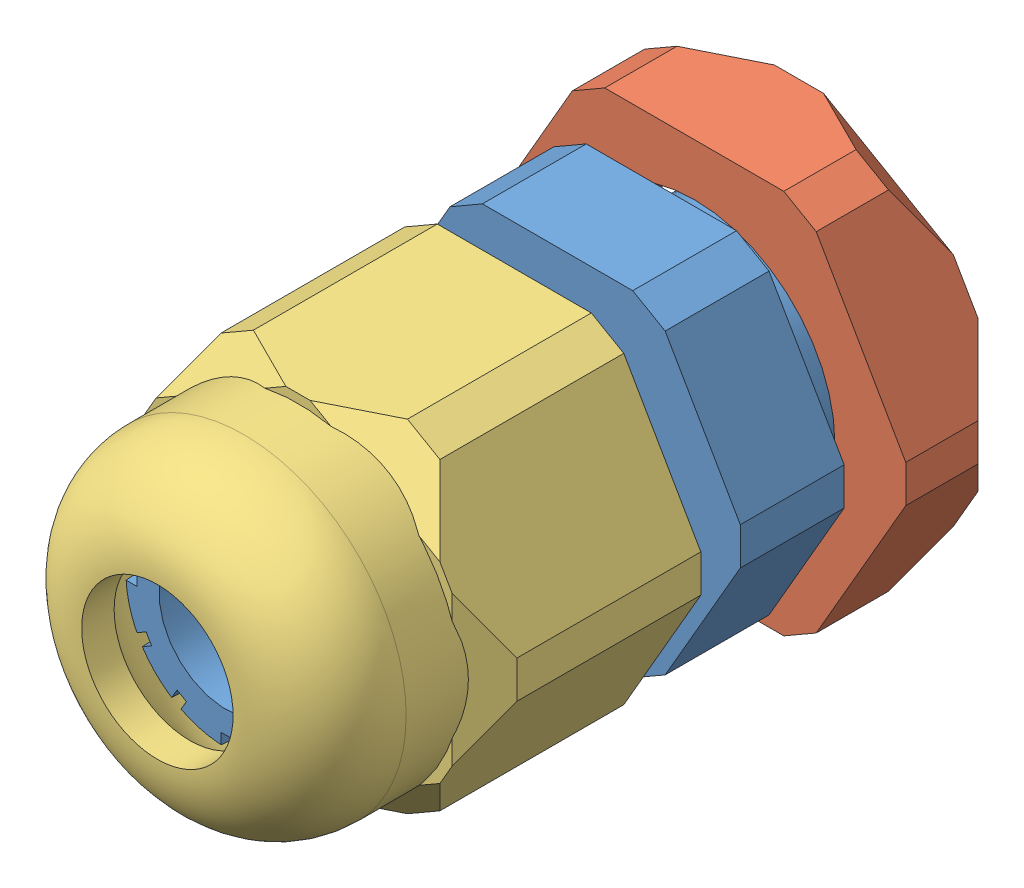
SolidWorks assembly PG7-CableGland, configuration Default. Lengths in mm.
Overall size (19.55 17.8 31.5).
3 component instances, 3 part files, 6 mates.
Components (placement in the parent):
- PG7-CableGland-Body-1: PG7-CableGland-Body [Default] at (0.0823 -0.2161 28.3183) size (16.9 15.5 28.32)
- PG7-CableGland-Back-1: PG7-CableGland-Back [Default] at (0.0823 -0.2161 17.1583) size (19.55 17.8 4.84)
- PG7-CableGland-Cap-1: PG7-CableGland-Cap [Default] at (0.0823 -0.2161 30.3183) size (17.24 15.8 16.5)
Mates (geometry in assembly coordinates):
- Concentric1: concentric anti-aligned: cylinder of PG7-CableGland-Body-1 through (0.0823 -0.2161 15.3183) axis (0 0 1) radius 5.15; cylinder of PG7-CableGland-Back-1 through (0.0823 -0.2161 21.9983) axis (0 0 -1) radius 6.5
- Concentric2: concentric aligned: cylinder of PG7-CableGland-Body-1 through (0.0823 -0.2161 15.3183) axis (0 0 1) radius 5.15; cylinder of PG7-CableGland-Cap-1 through (0.0823 -0.2161 30.3173) axis (0 0 1) radius 6.5
- Parallel1: parallel aligned: plane of PG7-CableGland-Body-1 through (4.5568 7.5339 23.5183) normal (0 1 0); plane of PG7-CableGland-Cap-1 through (4.6434 7.6839 40.3183) normal (0 1 0)
- Parallel2: parallel aligned: plane of PG7-CableGland-Body-1 through (4.5568 7.5339 23.5183) normal (0 1 0); plane of PG7-CableGland-Back-1 through (5.2208 8.6839 21.9983) normal (0 1 0)
- Distance2: distance = 2 mm anti-aligned: plane of PG7-CableGland-Body-1 through (0.0823 -0.2161 28.3183) normal (0 0 1); plane of PG7-CableGland-Cap-1 through (0.0823 -0.2161 30.3183) normal (0 0 -1)
- Distance3: distance = 1.52 mm anti-aligned: plane of PG7-CableGland-Back-1 through (0.0823 -0.2161 21.9983) normal (0 0 1); plane of PG7-CableGland-Body-1 through (0.0823 -0.2161 23.5183) normal (0 0 -1)
